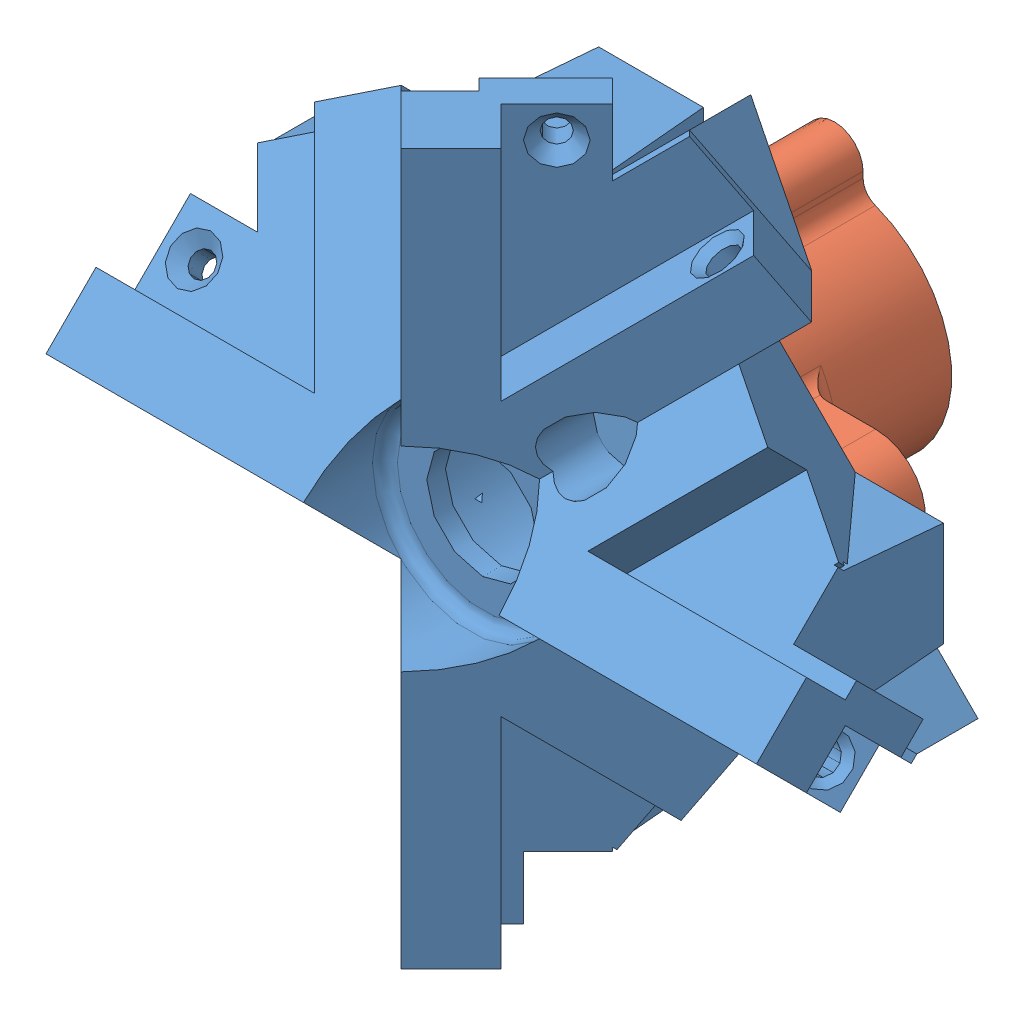
SolidWorks assembly Assem1, configuration Default. Lengths in mm.
Overall size (45.21 45.21 40.12).
2 component instances, 2 part files, 2 mates.
Components (placement in the parent):
- wackCorner2-1: wackCorner2 [Default] at origin size (45.21 45.21 15.9)
- outlet attempt-1: outlet attempt [Default] at (0 0 18.1577) x (0.408248 -0.707107 -0.57735) z (0.408248 0.707107 -0.57735) size (26.99 26.26 21.71)
Mates (geometry in assembly coordinates):
- Coincident1: coincident anti-aligned: line of wackCorner2-1 through (0 0 117.3006) axis (0 0 1); line of outlet attempt-1 through (0 0 155.7301) axis (0 0 -1)
- Coincident2: coincident anti-aligned: plane of wackCorner2-1 through (3.3335 0 144.907) normal (0 0 -1); plane of outlet attempt-1 through (3.7313 -6.4627 144.907) normal (0 0 1)
